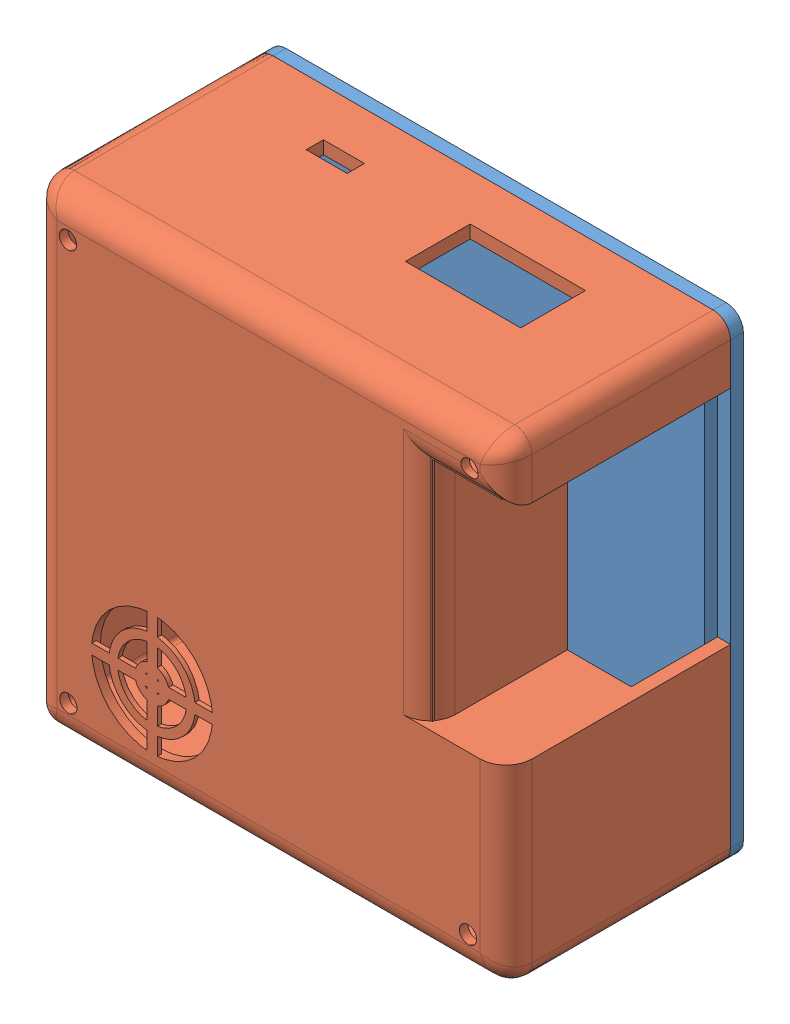
SolidWorks assembly Emsamble de base y tapa2b, configuration Predeterminado. Lengths in mm.
Overall size (110 110 55.01).
2 component instances, 2 part files, 3 mates.
Components (placement in the parent):
- 01_Base 124x107.7x6mm-1: 01_Base 124x107.7x6mm [Predeterminado] at (-5.9586 0.3192 124.1) size (110 110 11)
- 02b_tapa-1: 02b_tapa [Predeterminado] at (-5.9586 0.3192 127.1) size (110 110 52.01)
Mates (geometry in assembly coordinates):
- Coincidente1: coincident: plane of 01_Base 124x107.7x6mm-1 through (-57.9586 -51.6808 130.1) normal (0 -1 0); plane of 02b_tapa-1 through (-57.9586 -51.6808 177.9961) normal (0 1 0)
- Coincidente2: coincident: plane of 01_Base 124x107.7x6mm-1 through (46.0414 52.3192 130.1) normal (1 0 0); plane of 02b_tapa-1 through (46.0414 52.3192 177.9961) normal (-1 0 0)
- Coincidente3: coincident: plane of 01_Base 124x107.7x6mm-1 through (-56.9586 51.3192 127.1) normal (0 0 1); plane of 02b_tapa-1 through (-5.9586 0.3192 127.9961) normal (0 0 -1)
